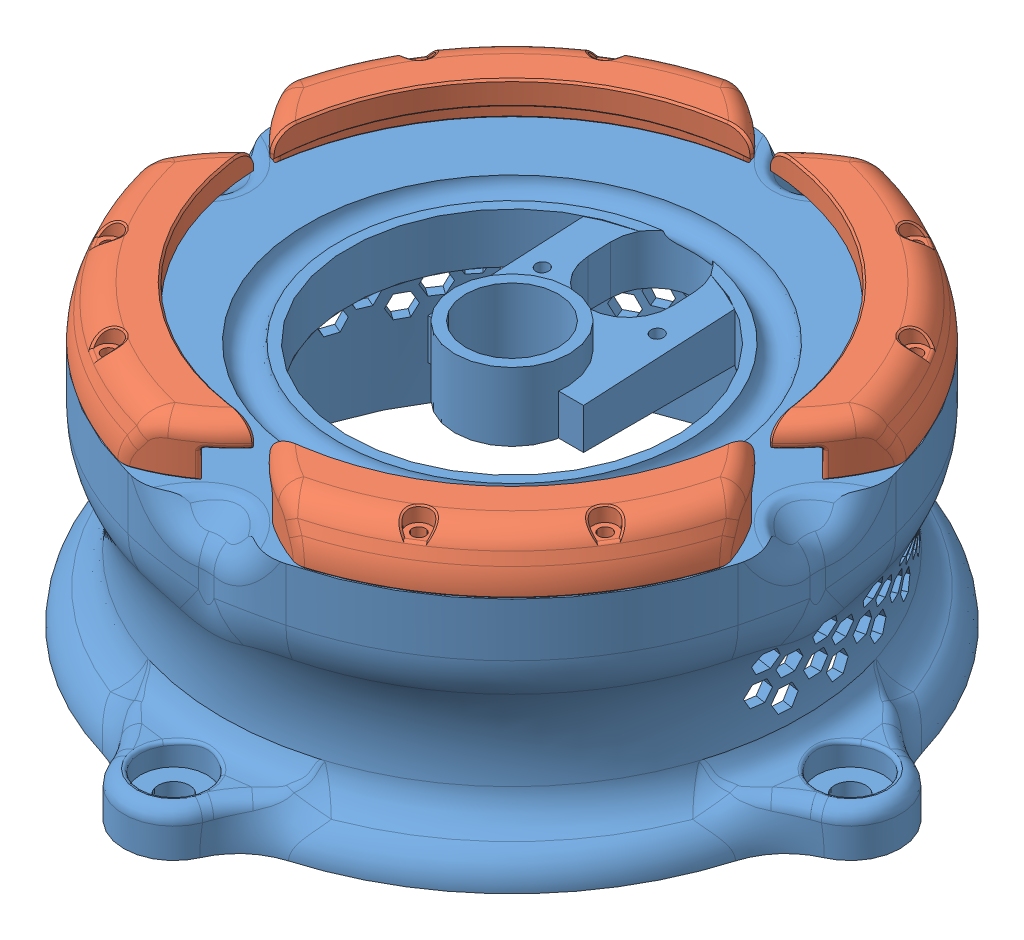
SolidWorks assembly 2.1 Support, configuration Domyślna. Lengths in mm.
Overall size (209.5 80.6 209.5).
5 component instances, 2 part files, 15 mates.
Components (placement in the parent):
- 2.1.1 Support base-1: 2.1.1 Support base [Domyślna] at (1.0093 68 3.9829) x (0 0 -1) z (0 1 0) size (209.5 209.5 67.16)
- 2.1.2 SegmentedRing-1: 2.1.2 SegmentedRing [Domyślna] at (0 66 0) x (0 0 -1) z (1 0 0) size (79.32 14.71 79.31)
- 2.1.2 SegmentedRing-2: 2.1.2 SegmentedRing [Domyślna] at (0 66 0) size (79.32 14.71 79.31)
- 2.1.2 SegmentedRing-3: 2.1.2 SegmentedRing [Domyślna] at (0 66 0) x (0 0 1) z (-1 0 0) size (79.32 14.71 79.31)
- 2.1.2 SegmentedRing-4: 2.1.2 SegmentedRing [Domyślna] at (0 66 0) x (-1 0 0) z (0 0 -1) size (79.32 14.71 79.31)
Mates (geometry in assembly coordinates):
- Wspólnie2: coincident anti-aligned: plane of 2.1.1 Support base-1 through (1.0093 68 0) normal (0 0 -1); plane of assembly through (0 0 0) normal (0 0 1)
- Wspólnie4: coincident anti-aligned: plane of 2.1.1 Support base-1 through (1.0093 0 3.9829) normal (0 -1 0); plane of assembly through (0 0 0) normal (0 1 0)
- Wspólnie5: coincident anti-aligned: plane of 2.1.1 Support base-1; plane of assembly through (0 0 0) normal (1 0 0)
- Wspólnie6: coincident anti-aligned: plane of 2.1.1 Support base-1 through (0 66 0) normal (0 1 0); plane of 2.1.2 SegmentedRing-3 through (74 66 0) normal (0 -1 0)
- Wspólnie7: coincident anti-aligned: plane of 2.1.1 Support base-1 through (0 66 0) normal (0 1 0); plane of 2.1.2 SegmentedRing-1 through (-74 66 0) normal (0 -1 0)
- Wspólnie8: coincident anti-aligned: plane of 2.1.1 Support base-1 through (0 66 0) normal (0 1 0); plane of 2.1.2 SegmentedRing-2 through (0 66 -74) normal (0 -1 0)
- Wspólnie9: coincident anti-aligned: plane of 2.1.1 Support base-1 through (0 66 0) normal (0 1 0); plane of 2.1.2 SegmentedRing-4 through (0 66 74) normal (0 -1 0)
- Koncentryczne1: concentric aligned: circle of 2.1.1 Support base-1; circle of 2.1.2 SegmentedRing-3
- Koncentryczne2: concentric aligned: circle of 2.1.1 Support base-1; circle of 2.1.2 SegmentedRing-4
- Koncentryczne3: concentric aligned: circle of 2.1.1 Support base-1; circle of 2.1.2 SegmentedRing-2
- Koncentryczne4: concentric aligned: circle of 2.1.1 Support base-1; circle of 2.1.2 SegmentedRing-1
- Wspólnie10: coincident aligned: plane of 2.1.2 SegmentedRing-1 through (0 66 0) normal (1 0 0); plane of assembly through (0 0 0) normal (1 0 0)
- Wspólnie13: coincident aligned: plane of 2.1.2 SegmentedRing-2 through (0 66 0) normal (0 0 1); plane of assembly through (0 0 0) normal (0 0 1)
- Wspólnie14: coincident anti-aligned: plane of 2.1.2 SegmentedRing-3 through (0 66 0) normal (-1 0 0); plane of assembly through (0 0 0) normal (1 0 0)
- Wspólnie15: coincident anti-aligned: plane of 2.1.2 SegmentedRing-4 through (0 66 0) normal (0 0 -1); plane of assembly through (0 0 0) normal (0 0 1)
